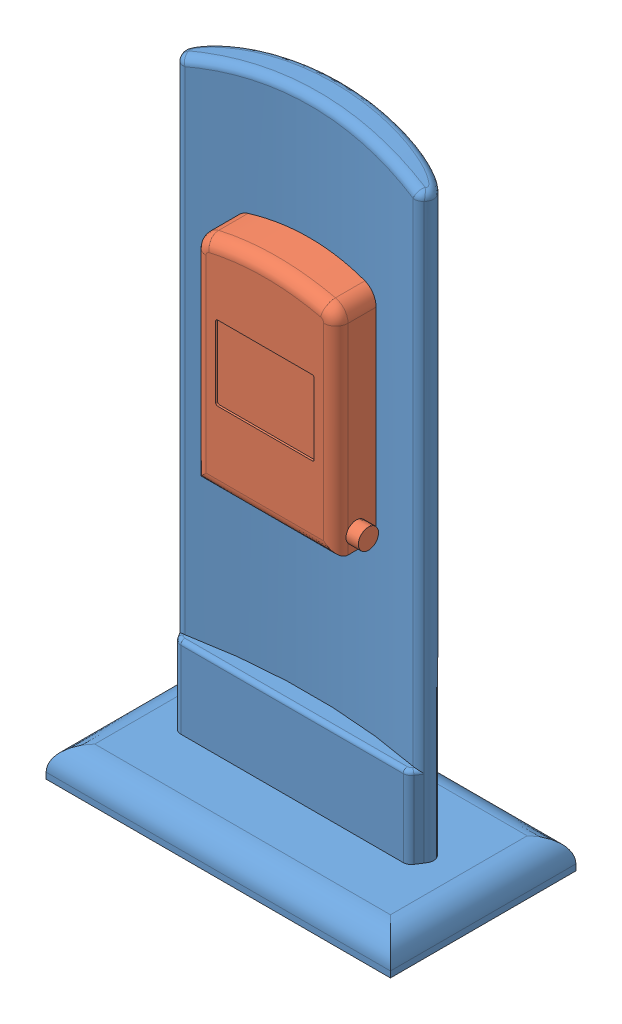
SolidWorks assembly Assem1, configuration Default. Lengths in mm.
Overall size (848.84 1586.92 457.2).
2 component instances, 2 part files, 3 mates.
Components (placement in the parent):
- wall latch-1: wall latch [Default] at (683.3049 79.857 1237.1254) size (848.84 1586.92 457.2)
- removable batch-1: removable batch [Default] at (682.8049 4.857 1239.1084) size (380 550 129.82)
Mates (geometry in assembly coordinates):
- Coincident1: coincident: plane of wall latch-1 through (683.3049 79.857 1215.1254) normal (0 0 1); plane of ? through (269.3498 4.857 1215.1254) normal (0 0 -1)
- Coincident4: coincident: plane of wall latch-1 through (683.3049 1189.857 1237.1254) normal (0 1 0); plane of ? through (83.3678 1189.857 1344.9514) normal (0 -1 0)
- Coincident8: coincident: plane of assembly; plane of assembly; plane of wall latch-1 through (487.8229 1189.857 1227.1254) normal (1 0 0); plane of removable batch-1 through (487.8229 1229.857 1344.9514) normal (-1 0 0)
